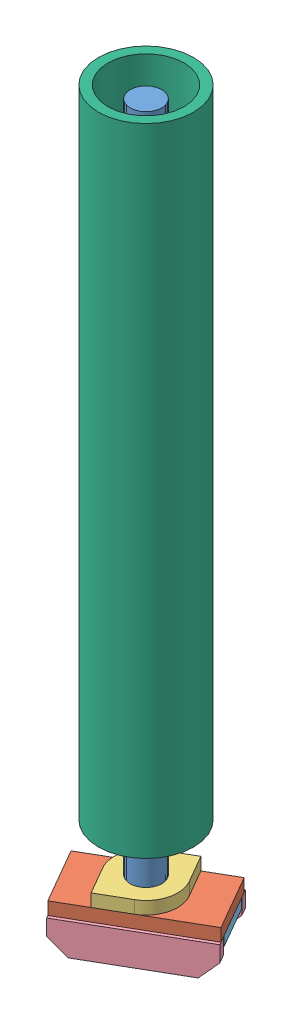
SolidWorks assembly Крепление10, configuration По умолчанию. Lengths in mm.
Overall size (45.64 233.82 39.05).
8 component instances, 6 part files, 22 mates.
Components (placement in the parent):
- БолтМ10-1: БолтМ10 [По умолчанию] at origin size (17 228 19.63)
- ПластинаСТ2010-1: ПластинаСТ2010 [По умолчанию] at (-12.3205 8 18.6603) x (0.866025 0 -0.5) z (0.5 0 0.866025) size (40 4 20)
- Ромб10-1: Ромб10 [По умолчанию] at (-3.6603 12 13.6603) x (0.866025 0 -0.5) z (0.5 0 0.866025) size (20 4 20)
- Косынка-1: Косынка [По умолчанию] at (-11.8205 8 19.5263) x (-0.5 0 -0.866025) z (-0.866025 0 0.5) size (3 10 40)
- Косынка-2: Косынка [По умолчанию] at (-21.3205 8 3.0718) x (-0.5 0 -0.866025) z (-0.866025 0 0.5) size (3 10 40)
- Накладка-1: Накладка [По умолчанию] at (12.4103 5 1.4952) x (0.866025 0 -0.5) z (0.5 0 0.866025) size (10 3 15)
- Накладка-2: Накладка [По умолчанию] at (-4.9103 8 11.4952) x (-0.866025 0 0.5) z (0.5 0 0.866025) size (10 3 15)
- Труба-1: Труба [По умолчанию] at (0 31 0) size (30 200.82 30)
Mates (geometry in assembly coordinates):
- Совпадение1: coordinate: point of БолтМ10-1
- Параллельность2: parallel aligned: plane of БолтМ10-1 through (8.5 8 4.9075) normal (1 0 0); plane of assembly through (0 0 0) normal (1 0 0)
- Совпадение2: coincident anti-aligned: plane of БолтМ10-1 through (0 8 0) normal (0 1 0); plane of ПластинаСТ2010-1 through (-12.3205 8 18.6603) normal (0 -1 0)
- Концентричный1: concentric anti-aligned: cylinder of БолтМ10-1 through (0 228 0) axis (0 -1 0) radius 5; cylinder of ПластинаСТ2010-1 through (0 8 0) axis (0 1 0) radius 5
- Параллельность3: parallel aligned: plane of БолтМ10-1 through (0 8 9.815) normal (0.5 0 0.866025); plane of ПластинаСТ2010-1 through (-12.3205 12 18.6603) normal (0.5 0 0.866025)
- Концентричный2: concentric anti-aligned: cylinder of БолтМ10-1 through (0 228 0) axis (0 -1 0) radius 5; cylinder of Ромб10-1 through (0 12 0) axis (0 1 0) radius 5
- Совпадение3: coincident anti-aligned: plane of ПластинаСТ2010-1 through (-12.3205 12 18.6603) normal (0 1 0); plane of Ромб10-1 through (0 12 0) normal (0 -1 0)
- Совпадение4: coincident aligned: plane of ПластинаСТ2010-1 through (-12.3205 12 18.6603) normal (0.5 0 0.866025); plane of Ромб10-1 through (-3.6603 16 13.6603) normal (0.5 0 0.866025)
- Совпадение5: coincident anti-aligned: plane of ПластинаСТ2010-1 through (-12.3205 8 18.6603) normal (0 -1 0); plane of Косынка-2 through (-22.8205 8 0.4737) normal (0 1 0)
- Расстояние2: distance = 1 mm aligned: plane of Косынка-2 through (-22.8205 8 0.4737) normal (-0.5 0 -0.866025); plane of ПластинаСТ2010-1 through (-22.3205 12 1.3397) normal (-0.5 0 -0.866025)
- Совпадение7: coincident aligned: plane of ПластинаСТ2010-1 through (-12.3205 12 18.6603) normal (-0.866025 0 0.5); plane of Косынка-2 through (-22.8205 3 0.4737) normal (-0.866025 0 0.5)
- Совпадение8: coincident anti-aligned: plane of ПластинаСТ2010-1 through (-12.3205 8 18.6603) normal (0 -1 0); plane of Косынка-1 through (-13.3205 8 16.9282) normal (0 1 0)
- Расстояние3: distance = 1 mm aligned: plane of Косынка-1 through (-11.8205 8 19.5263) normal (0.5 0 0.866025); plane of ПластинаСТ2010-1 through (-12.3205 12 18.6603) normal (0.5 0 0.866025)
- Совпадение10: coincident aligned: plane of Косынка-1 through (-13.3205 3 16.9282) normal (-0.866025 0 0.5); plane of Косынка-2 through (-22.8205 3 0.4737) normal (-0.866025 0 0.5)
- Совпадение11: coincident aligned: plane of ПластинаСТ2010-1 through (22.3205 12 -1.3397) normal (0.866025 0 -0.5); plane of Накладка-1 through (21.0705 8 -3.5048) normal (0.866025 0 -0.5)
- Расстояние4: distance = 2.5 mm aligned: plane of Накладка-1 through (12.4103 8 1.4952) normal (0.5 0 0.866025); plane of ПластинаСТ2010-1 through (-12.3205 12 18.6603) normal (0.5 0 0.866025)
- Совпадение13: coincident anti-aligned: plane of ПластинаСТ2010-1 through (-12.3205 8 18.6603) normal (0 -1 0); plane of Накладка-1 through (8.6603 8 -5) normal (0 1 0)
- Совпадение14: coincident anti-aligned: plane of ПластинаСТ2010-1 through (-12.3205 8 18.6603) normal (0 -1 0); plane of Накладка-2 through (-8.6603 8 5) normal (0 1 0)
- Совпадение15: coincident aligned: plane of ПластинаСТ2010-1 through (-12.3205 12 18.6603) normal (-0.866025 0 0.5); plane of Накладка-2 through (-13.5705 5 16.4952) normal (-0.866025 0 0.5)
- Совпадение16: coincident aligned: plane of Накладка-1 through (4.9103 8 -11.4952) normal (-0.5 0 -0.866025); plane of Накладка-2 through (-12.4103 5 -1.4952) normal (-0.5 0 -0.866025)
- Концентричный3: concentric aligned: cylinder of БолтМ10-1 through (0 228 0) axis (0 -1 0) radius 5; cylinder of Труба-1 through (0 31 0) axis (0 -1 0) radius 12
- Расстояние5: distance = 15 mm anti-aligned: plane of Труба-1 through (0 31 -5) normal (0 -1 0); plane of Ромб10-1 through (0 16 0) normal (0 1 0)
